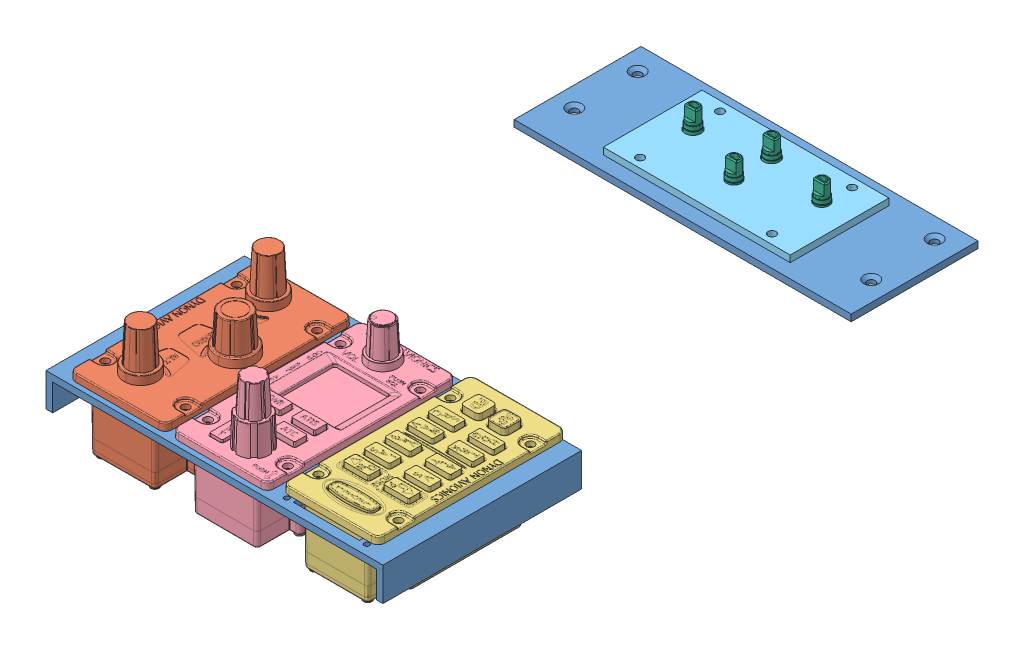
SolidWorks assembly Radio assemblyv2, configuration Default. Lengths in mm.
Overall size (201.11 66.42 309.26).
28 component instances, 17 part files, 4 mates.
Components (placement in the parent):
- Radio assembly-1: Radio assembly [Default] at (58.1354 -24.3244 -127.4728) size (201.11 66.42 309.26)
  - Radio stack Bottom-1: Radio stack Bottom [Default] at (52.5504 228.246 225.1405) size (201.11 15.88 309.26)
  - SV-KNOB-PANEL_Knob_Control_Panel_Horizontal_Sand_Filled.igs-1: SV-KNOB-PANEL_Knob_Control_Panel_Horizontal_Sand_Filled.igs [Default] at (75.9593 231.421 392.7624) x (0.999994 0 -0.003503) z (0 1 0) size (52.38 89.72 58.92)
  - SV-AP-PANEL_Autopilot_Control_Panel_Horizontal_Sand_Filled.igs-1: SV-AP-PANEL_Autopilot_Control_Panel_Horizontal_Sand_Filled.igs [Default] at (173.433 231.421 388.7848) x (1 0 0) z (0 1 0) size (45.73 89.72 38.5)
  - SV-COM-PANEL_Vertical_Solid_Model.igs-1: SV-COM-PANEL_Vertical_Solid_Model.igs [Default] at (101.8389 231.421 437.4175) x (0.999995 0 0.003205) z (0 1 0) size (45.73 89.72 66.42)
  - Lighting front plate-1: Lighting front plate [Default] at (52.5504 231.421 225.1405) x (1 0 0) z (0 1 0) size (88.9 46.99 3.17)
  - EC12D1524403.step-4: EC12D1524403.step [Default] at (102.1513 226.8481 189.6817) x (1 0 0) z (0 1 0) size (14.15 12.96 20.98)
  - untitled.step-1: untitled.step [Default] at (88.9882 225.2956 173.1478) x (0 0 1) z (0 1 0) size (36.53 79.25 3.18)
    - Packages.step-1: Packages.step [Default] at origin size (35.84 78.38 3.18)
      - 78XXL.step-1: 78XXL.step [Default] at (16.51 28.448 -0.0525) x (0 -1 0) z (0 0 -1) size (6.6 3.05 1.47)
      - 32A_ATM.step-1: 32A_ATM.step [Default] at (16.764 58.42 -0.0525) x (0 1 0) z (0 0 -1) size (10.48 11.01 0.1)
      - PINHEADER_2R03_100MIL.step-1: PINHEADER_2R03_100MIL.step [Default] at (4.064 55.626 -0.0525) x (0 -1 0) z (0 0 -1) size (7.77 5.23 0.1)
      - F09V.step-1: F09V.step [Default] at (30.988 66.802 -0.0525) x (0 1 0) z (0 0 -1) size (32.16 12.6 0.1)
      - F09V.step-2: F09V.step [Default] at (30.988 20.574 -0.0525) x (0 1 0) z (0 0 -1) size (32.16 12.6 0.1)
      - C1206.step-1: C1206.step [Default] at (21.082 22.098 -0.0525) x (-1 0 0) z (0 0 -1) size (3.2 1.6 1.3)
      - C1206.step-2: C1206.step [Default] at (21.082 33.528 -0.0525) x (1 0 0) z (0 0 -1) size (3.2 1.6 1.3)
      - EC12S.step-1: EC12S.step [Default] at (15.494 73.66 1.5525) x (0 -1 0) z (0 0 1) size (14.5 14.11 0.1)
      - EC12S.step-2: EC12S.step [Default] at (9.144 43.434 1.5525) x (0 -1 0) z (0 0 1) size (14.5 14.11 0.1)
      - EC12S.step-3: EC12S.step [Default] at (16.256 12.954 1.5525) x (0 -1 0) z (0 0 1) size (14.5 14.11 0.1)
      - EC12S.step-4: EC12S.step [Default] at (27.178 43.688 1.5525) x (0 -1 0) z (0 0 1) size (14.5 14.11 0.1)
    - Board.step-1: Board.step [Default] at origin size (36.32 79.25 1.5)
    - 1-copper.step-1: 1-copper.step [Default] at (0 0 1.5) size (32.74 75.01 0.07)
    - 16-copper.step-1: 16-copper.step [Default] at (0 0 -0.035) size (32.74 75.01 0.07)
    - 1-soldermask.step-1: 1-soldermask.step [Default] at (0 0 1.5) size (36.32 79.25 0.05)
    - 16-soldermask.step-1: 16-soldermask.step [Default] at origin size (36.32 79.25 0.05)
- EC12D1524403.step-3: EC12D1524403.step [Default] at (190.5945 202.0966 55.1581) x (1 0 0) z (0 1 0) size (14.15 12.96 20.98)
- EC12D1524403.step-4: EC12D1524403.step [Default] at (220.8667 202.0966 61.4829) x (1 0 0) z (0 1 0) size (14.15 12.96 20.98)
- EC12D1524403.step-5: EC12D1524403.step [Default] at (190.7551 202.0966 73.2157) x (1 0 0) z (0 1 0) size (14.15 12.96 20.98)
Mates (geometry in assembly coordinates):
- Coincident3: coincident anti-aligned: plane of Radio assembly-1/Lighting front plate-1 through (110.6857 207.0966 97.6678) normal (0 -1 0); plane of EC12D1524403.step-3 through (192.0945 207.0966 53.6431) normal (0 1 0)
- Coincident4: coincident anti-aligned: plane of Radio assembly-1/Lighting front plate-1 through (110.6857 207.0966 97.6678) normal (0 -1 0); plane of EC12D1524403.step-4 through (222.3667 207.0966 59.9679) normal (0 1 0)
- Parallel3: parallel aligned: line of Radio assembly-1/EC12D1524403.step-4 through (153.9982 199.0237 62.2089) axis (0.846138 0.532964 0); line of EC12D1524403.step-4 through (214.5782 198.5966 61.4829) axis (0.846138 0.532964 0)
- Coincident6: coincident anti-aligned: plane of Radio assembly-1/Lighting front plate-1 through (110.6857 207.0966 97.6678) normal (0 -1 0); plane of EC12D1524403.step-5 through (192.2551 207.0966 71.7007) normal (0 1 0)
